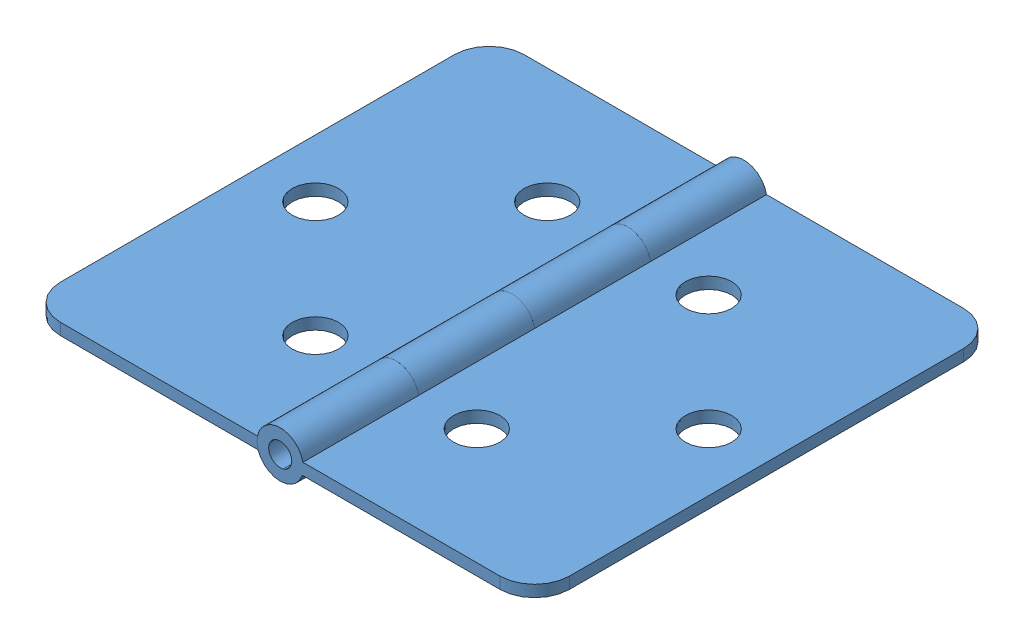
SolidWorks assembly Assem2, configuration Default. Lengths in mm.
Overall size (43.92 4 40).
2 component instances, 1 part files, 2 mates.
Components (placement in the parent):
- ass3_2SLDPRT-1: ass3_2SLDPRT [Default] at (-23.7109 17.4362 21.7003) size (23.96 4 40)
- ass3_2SLDPRT-3: ass3_2SLDPRT [Default] at (-39.4175 17.4362 -18.2997) x (-1 0 0) z (0 0 -1) size (23.96 4 40)
Mates (geometry in assembly coordinates):
- Hinge1: hinge anti-aligned: cylinder of ass3_2SLDPRT-3 through (-31.5642 18.0442 -8.2997) axis (0 0 -1) radius 1; cylinder of ass3_2SLDPRT-3 through (-31.5642 18.0442 -8.2997) axis (0 0 1) radius 1; plane of ass3_2SLDPRT-1 through (-39.4175 17.4362 -8.2997) normal (0 0 1); plane of ass3_2SLDPRT-1 through (-23.7109 17.4362 -8.2997) normal (0 0 -1)
- LimitAngle1: limit planar angle = 3.141593 rad anti-aligned: plane of ass3_2SLDPRT-3 through (-39.4175 18.4362 21.7003) normal (0 1 0); plane of ass3_2SLDPRT-1 through (-23.7109 18.4362 -18.2997) normal (0 1 0)
